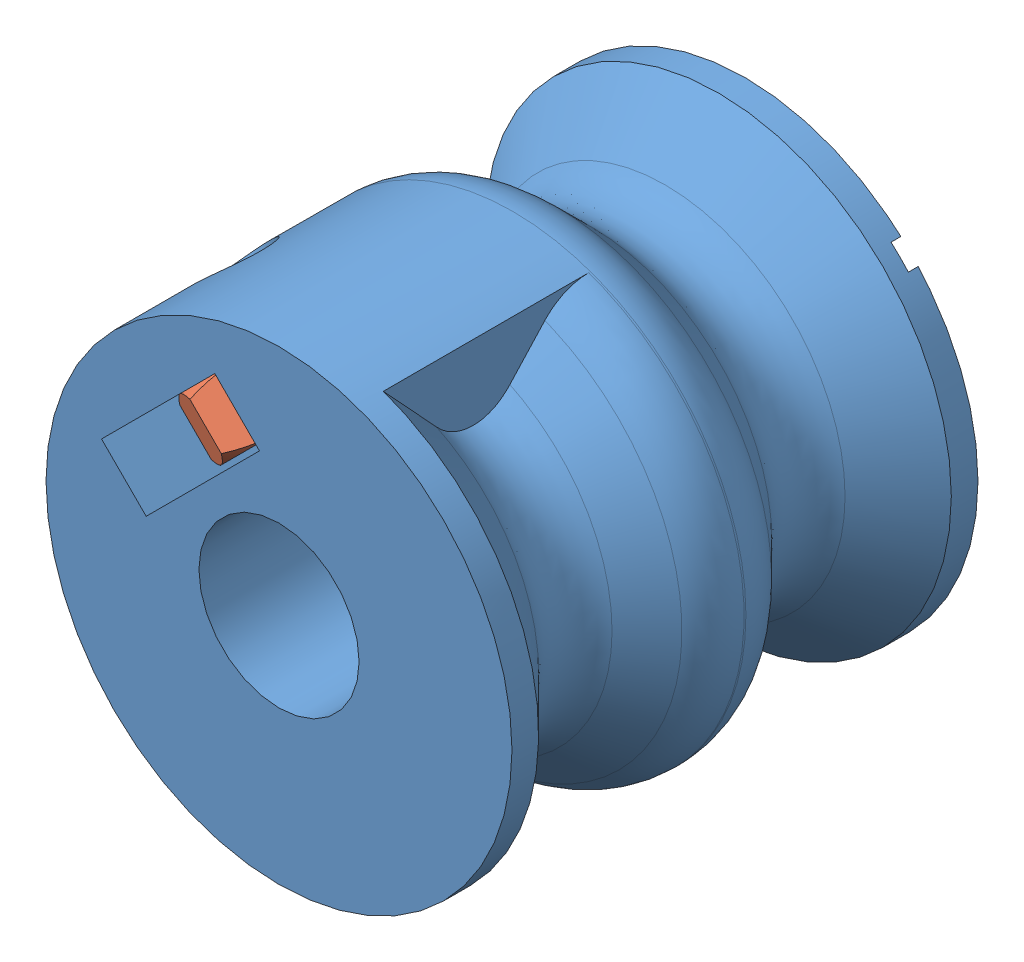
SolidWorks assembly Wing Fold Mechanism Push-Pull Detents, configuration Default. Lengths in mm.
Overall size (19.05 19.05 19.05).
3 component instances, 3 part files, 0 mates.
Components (placement in the parent):
- Wing Fold Mechanism Push-Pull Detents-1: Wing Fold Mechanism Push-Pull Detents [Default] at origin size (19.05 19.05 19.05)
- 91841A005-1: 91841A005 [Default] at (-4.0972 4.0972 14.2875) x (0.707107 0.707107 0) z (0 0 1) size (6.35 2.56 7.33)
- 92311A105-1: 92311A105 [Default] at (-4.0904 4.0904 14.2875) x (0.707107 0.707107 0) z (-0.707107 0.707107 0) size (2.91 2.9 4.84)
